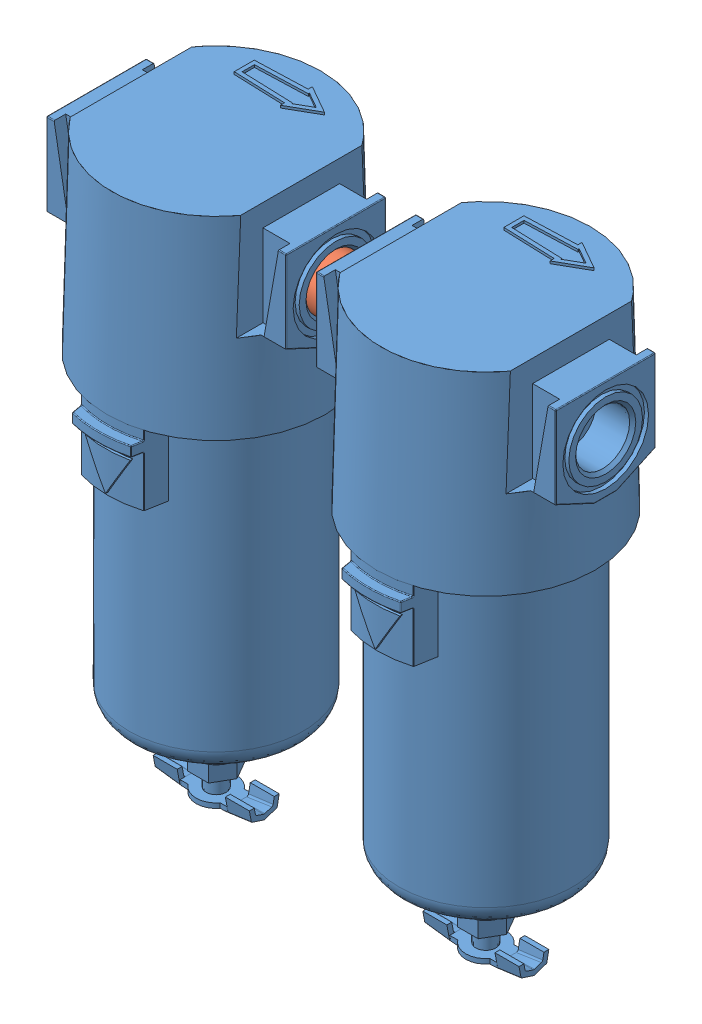
SolidWorks assembly ReadingTech_3P-020-M03-DCP, configuration Default. Lengths in mm.
Overall size (161.38 182.88 72.07).
3 component instances, 2 part files, 3 mates.
Components (placement in the parent):
- ReadingTech_3P-020-M03-P-1: ReadingTech_3P-020-M03-P [Default] at (-10.9463 105.8002 -5.9264) size (75.95 182.88 72.07)
- ReadingTech_3P-020-M03-P-2: ReadingTech_3P-020-M03-P [Default] at (74.4856 105.8002 -5.9264) size (75.95 182.88 72.07)
- ReadingTech- 20cfm_connector_.375in-1: ReadingTech- 20cfm_connector_.375in [Default] at (37.4847 82.9402 -5.9264) x (0 1 0) z (0 0 1) size (17.14 11.43 17.14)
Mates (geometry in assembly coordinates):
- Coincident1: coincident anti-aligned: circle of ReadingTech_3P-020-M03-P-1; circle of ReadingTech- 20cfm_connector_.375in-1
- Coincident2: coincident aligned: circle of ReadingTech_3P-020-M03-P-2; circle of ReadingTech- 20cfm_connector_.375in-1
- Coincident3: coincident aligned: plane of ReadingTech_3P-020-M03-P-1 through (-10.9463 105.8002 6.2148) normal (0 0 1); plane of ReadingTech_3P-020-M03-P-2 through (74.4856 105.8002 6.2148) normal (0 0 1)
